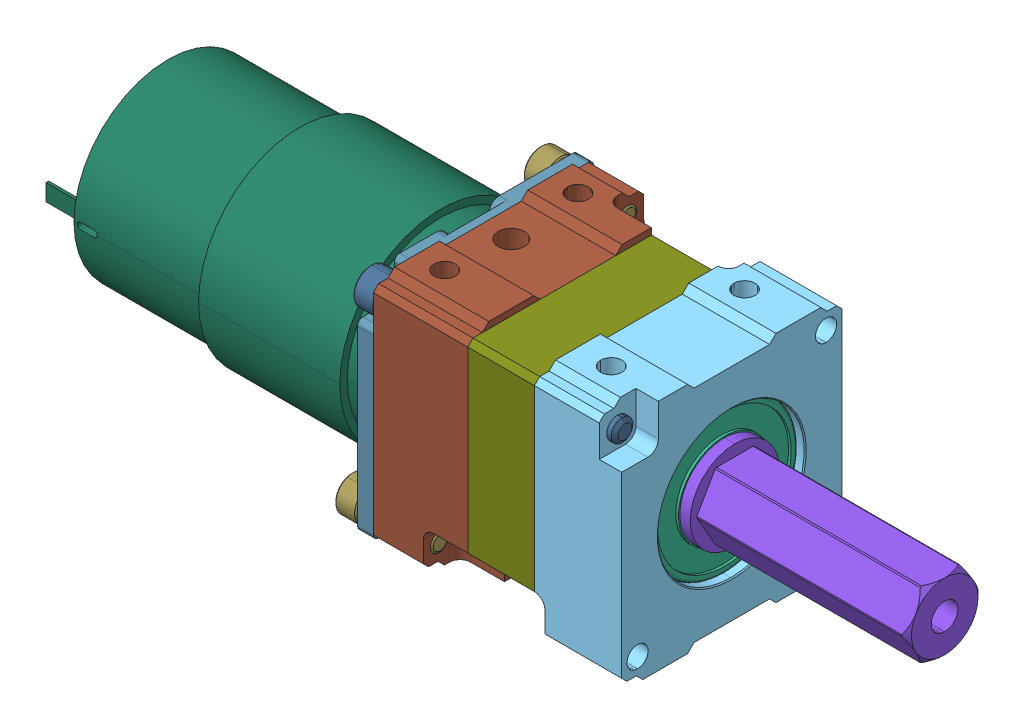
SolidWorks assembly VersaPlanetary_v2_Single_Stage_10_1_with_RS_550, configuration Default. Lengths in mm.
Overall size (155.67 50.92 52.65).
30 component instances, 19 part files, 0 mates.
Components (placement in the parent):
- VersaPlanetary_v2_Single_Stage_10_1_with_RS_550.STEP-1: VersaPlanetary_v2_Single_Stage_10_1_with_RS_550.STEP [Default] at origin size (155.67 50.92 52.65)
  - 217-2820 Rev1_Public.STEP-1: 217-2820 Rev1_Public.STEP [Default] at (-4.6546 22.225 0) x (0 -0.456494 0.889726) z (-1 0 0) size (39.22 38.88 17.4)
    - 217-2625-100.STEP-1: 217-2625-100.STEP [Default] at origin size (39.22 38.88 12.7)
      - 217-2625-008 Rev1.STEP-1: 217-2625-008 Rev1.STEP [Default] at origin size (34.7 34.7 4.7)
      - 217-2625-010 Rev1.STEP-1: 217-2625-010 Rev1.STEP [Default] at (0 10.193 3.65) x (0.999813 0.019336 0) z (0 0 1) size (4 4 12)
      - 217-2625-010 Rev1.STEP-2: 217-2625-010 Rev1.STEP [Default] at (8.691 -5.3258 3.65) size (4 4 12)
      - 217-2625-010 Rev1.STEP-3: 217-2625-010 Rev1.STEP [Default] at (-8.691 -5.3258 3.65) size (4 4 12)
      - 217-2625-005 Rev1_Planet_Revolving_Follower01.STEP-1: 217-2625-005 Rev1_Planet_Revolving_Follower01.STEP [Default] at (8.691 -5.3258 6.35) x (0.932816 0.360354 0) z (0 0 1) size (16.89 16.89 8)
      - 217-2625-005 Rev1_Planet_Revolving_Follower01.STEP-2: 217-2625-005 Rev1_Planet_Revolving_Follower01.STEP [Default] at (-8.691 -5.3258 6.35) x (-0.932788 -0.360426 0) z (0 0 1) size (16.89 16.89 8)
      - 217-2625-005 Rev1_Planet_Revolving_Follower01.STEP-3: 217-2625-005 Rev1_Planet_Revolving_Follower01.STEP [Default] at (0 10.193 6.35) x (0.893583 0.448898 0) z (0 0 1) size (16.89 16.89 8)
    - 217-2625-007 Rev1_Public.STEP-1: 217-2625-007 Rev1_Public.STEP [Default] at (0 0 6.7) x (0.992772 0.120019 0) z (0 0 1) size (15.27 15.27 12.7)
  - 217-2625-026 Rev1.STEP-1: 217-2625-026 Rev1.STEP [Default] at (-6.5 22.225 0) x (0 -1 0) z (-1 0 0) size (44.45 42 18.12)
  - 217-2742-001 Rev4.STEP-1: 217-2742-001 Rev4.STEP [Default] at (0.2002 22.225 0) x (1 0 0) z (0 -0.092627 0.995701) size (7 28 28)
  - 217-2742-001 Rev4.STEP-2: 217-2742-001 Rev4.STEP [Default] at (8.2002 22.225 0) size (7 28 28)
  - 217-2625-017 Rev1_9714K61.STEP-1: 217-2625-017 Rev1_9714K61.STEP [Default] at (7.42 22.3002 -0.342) x (0 0.56703 0.823697) z (0 -0.823697 0.56703) size (28.51 4.98 27.43)
  - 217-2625-003 Rev1.STEP-1: 217-2625-003 Rev1.STEP [Default] at (7.4478 22.225 0) x (0 -1 0) z (1 0 0) size (17 17 64.11)
  - 217-2625-018 Rev1_98541A410.STEP-1: 217-2625-018 Rev1_98541A410.STEP [Default] at (-0.7046 22.225 0) x (1 0 0) z (0 -0.017452 0.999848) size (1 19.6 17.4)
  - 832-1750-Ring-Gear-Screw_SSA0832-0500ZC.STEP-1: 832-1750-Ring-Gear-Screw_SSA0832-0500ZC.STEP [Default] at (-30.7 4.725 -17.5) x (0 0.997447 0.071411) z (0 -0.071411 0.997447) size (6.73 48.51 6.73)
  - 832-1750-Ring-Gear-Screw_SSA0832-0500ZC.STEP-2: 832-1750-Ring-Gear-Screw_SSA0832-0500ZC.STEP [Default] at (-30.7 39.725 17.5) x (0 0.005929 0.999982) z (0 -0.999982 0.005929) size (6.73 48.51 6.73)
  - 217-2625-025 Rev1.STEP-1: 217-2625-025 Rev1.STEP [Default] at (-23.2 22.225 0) x (0 -1 0) z (-1 0 0) size (44.45 42 18)
  - 217-4649-002 Rev1_SSA0832-0500ZC.STEP-1: 217-4649-002 Rev1_SSA0832-0500ZC.STEP [Default] at (-33.7 4.2645 17.9605) x (0 0.33842 -0.940995) z (0 0.940995 0.33842) size (6.73 16.76 6.73)
  - 217-4649-002 Rev1_SSA0832-0500ZC.STEP-2: 217-4649-002 Rev1_SSA0832-0500ZC.STEP [Default] at (-33.7 40.1855 -17.9605) x (0 -0.308932 -0.951084) z (0 0.951084 -0.308932) size (6.73 16.76 6.73)
  - 217-4649-005 Rev1_SSA0003-008BA.STEP-1: 217-4649-005 Rev1_SSA0003-008BA.STEP [Default] at (-30.7 22.225 -12.5) x (0 -0.5 0.866025) z (0 0.866025 0.5) size (5.5 11 5.5)
  - 217-4649-005 Rev1_SSA0003-008BA.STEP-2: 217-4649-005 Rev1_SSA0003-008BA.STEP [Default] at (-30.7 22.225 12.5) x (0 -0.5 -0.866025) z (0 -0.866025 0.5) size (5.5 11 5.5)
  - 217-2822-001 Rev4.STEP-1: 217-2822-001 Rev4.STEP [Default] at (-32.2 22.225 0) x (0 1 0) z (-1 0 0) size (42 42 4.8)
  - BaneBots RS550.STEP-1: BaneBots RS550.STEP [Default] at (-83.738 22.225 0) x (0 0 1) z (1 0 0) size (38.61 38.57 77.9)
  - 217-2816-001 Rev1.STEP-1: 217-2816-001 Rev1.STEP [Default] at (-6.35 22.225 0) x (0 -1 0) z (1 0 0) size (42 42 14.51)
  - 217-4649-001 Rev1.STEP-1: 217-4649-001 Rev1.STEP [Default] at (-20.046 22.225 0) x (0 -1 0) z (1 0 0) size (18 18 13)
  - 217-4649-007 Rev1_94105A824.STEP-1: 217-4649-007 Rev1_94105A824.STEP [Default] at (-25.521 22.225 -6.7835) x (-0.996104 -0.088191 0) z (0 0 -1) size (4.83 4.83 4.77)
  - 217-2625-012 Rev1.STEP-1: 217-2625-012 Rev1.STEP [Default] at (-21.0318 22.225 0) x (0 0 1) z (-1 0 0) size (8.01 7.94 7.5)
